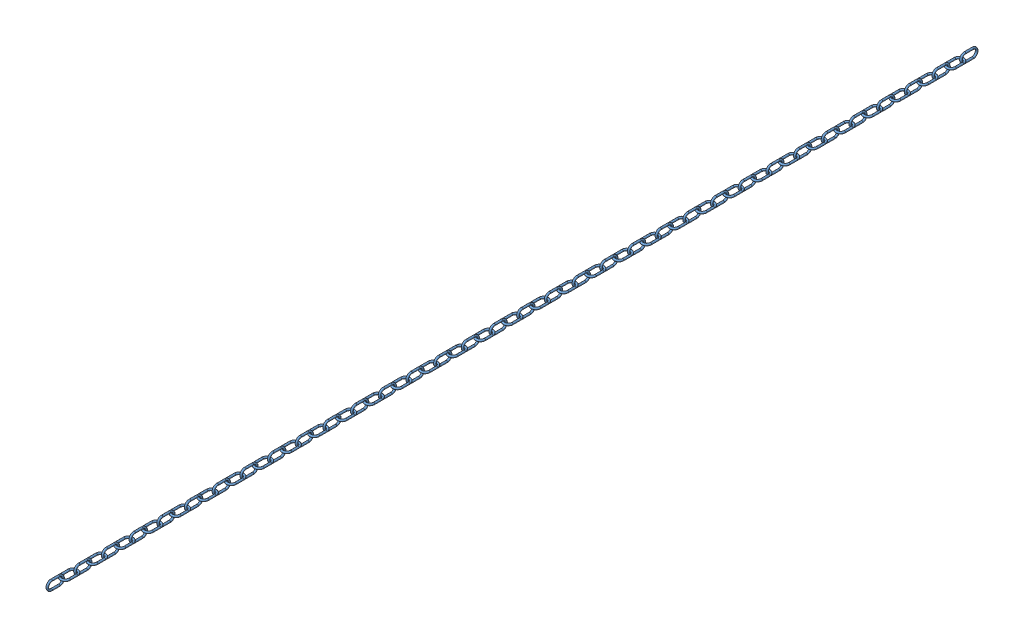
SolidWorks assembly GE-22026, configuration no u bolt. Lengths in mm.
Overall size (25.4 25.4 2349.5).
69 component instances, 2 part files, 9 mates.
Components (placement in the parent):
- GE-22355-01-1: GE-22355-01 [Default] at origin
- GE-22355-01-53: GE-22355-01 [Default] at (0 0 -34.925) x (0 1 0) z (0 0 1)
- GE-22355-01-19: GE-22355-01 [Default] at (0 0 -69.85)
- GE-22355-01-20: GE-22355-01 [Default] at (0 0 -139.7)
- GE-22355-01-21: GE-22355-01 [Default] at (0 0 -209.55)
- GE-22355-01-22: GE-22355-01 [Default] at (0 0 -279.4)
- GE-22355-01-23: GE-22355-01 [Default] at (0 0 -349.25)
- GE-22355-01-24: GE-22355-01 [Default] at (0 0 -419.1)
- GE-22355-01-25: GE-22355-01 [Default] at (0 0 -488.95)
- GE-22355-01-26: GE-22355-01 [Default] at (0 0 -558.8)
- GE-22355-01-27: GE-22355-01 [Default] at (0 0 -628.65)
- GE-22355-01-28: GE-22355-01 [Default] at (0 0 -698.5)
- GE-22355-01-29: GE-22355-01 [Default] at (0 0 -768.35)
- GE-22355-01-30: GE-22355-01 [Default] at (0 0 -838.2)
- GE-22355-01-31: GE-22355-01 [Default] at (0 0 -908.05)
- GE-22355-01-32: GE-22355-01 [Default] at (0 0 -977.9)
- GE-22355-01-33: GE-22355-01 [Default] at (0 0 -1047.75)
- GE-22355-01-54: GE-22355-01 [Default] at (0 0 -104.775) x (0 1 0) z (0 0 1)
- GE-22355-01-55: GE-22355-01 [Default] at (0 0 -174.625) x (0 1 0) z (0 0 1)
- GE-22355-01-56: GE-22355-01 [Default] at (0 0 -244.475) x (0 1 0) z (0 0 1)
- GE-22355-01-57: GE-22355-01 [Default] at (0 0 -314.325) x (0 1 0) z (0 0 1)
- GE-22355-01-58: GE-22355-01 [Default] at (0 0 -384.175) x (0 1 0) z (0 0 1)
- GE-22355-01-59: GE-22355-01 [Default] at (0 0 -454.025) x (0 1 0) z (0 0 1)
- GE-22355-01-60: GE-22355-01 [Default] at (0 0 -523.875) x (0 1 0) z (0 0 1)
- GE-22355-01-61: GE-22355-01 [Default] at (0 0 -593.725) x (0 1 0) z (0 0 1)
- GE-22355-01-62: GE-22355-01 [Default] at (0 0 -663.575) x (0 1 0) z (0 0 1)
- GE-22355-01-63: GE-22355-01 [Default] at (0 0 -733.425) x (0 1 0) z (0 0 1)
- GE-22355-01-64: GE-22355-01 [Default] at (0 0 -803.275) x (0 1 0) z (0 0 1)
- GE-22355-01-65: GE-22355-01 [Default] at (0 0 -873.125) x (0 1 0) z (0 0 1)
- GE-22355-01-66: GE-22355-01 [Default] at (0 0 -942.975) x (0 1 0) z (0 0 1)
- GE-22355-01-67: GE-22355-01 [Default] at (0 0 -1012.825) x (0 1 0) z (0 0 1)
- GE-22355-01-48: GE-22355-01 [Default] at (0 0 -1117.6)
- GE-22355-01-68: GE-22355-01 [Default] at (0 0 -1082.675) x (0 1 0) z (0 0 1)
- GE-22355-01-50: GE-22355-01 [Default] at (0 0 -1187.45)
- GE-22355-01-69: GE-22355-01 [Default] at (0 0 -1152.525) x (0 1 0) z (0 0 1)
- Ubolt_.25_.75_1.25-1: Ubolt_.25_.75_1.25 [3043T641] at (0 0 4.7625) x (-1 0 0) z (0 1 0) (suppressed, hidden)
- Ubolt_.25_.75_1.25-2: Ubolt_.25_.75_1.25 [3043T641] at (0 0 -1306.5125) x (-1 0 0) z (0 -1 0) (suppressed, hidden)
- GE-22355-01-52: GE-22355-01 [Default] at (0 0 -1257.3)
- GE-22355-01-70: GE-22355-01 [Default] at (0 0 -1222.375) x (0 1 0) z (0 0 1)
- GE-22355-01-71: GE-22355-01 [Default] at (0 0 -1327.15)
- GE-22355-01-72: GE-22355-01 [Default] at (0 0 -1397)
- GE-22355-01-73: GE-22355-01 [Default] at (0 0 -1466.85)
- GE-22355-01-74: GE-22355-01 [Default] at (0 0 -1536.7)
- GE-22355-01-75: GE-22355-01 [Default] at (0 0 -1606.55)
- GE-22355-01-76: GE-22355-01 [Default] at (0 0 -1676.4)
- GE-22355-01-77: GE-22355-01 [Default] at (0 0 -1746.25)
- GE-22355-01-78: GE-22355-01 [Default] at (0 0 -1816.1)
- GE-22355-01-79: GE-22355-01 [Default] at (0 0 -1885.95)
- GE-22355-01-80: GE-22355-01 [Default] at (0 0 -1955.8)
- GE-22355-01-81: GE-22355-01 [Default] at (0 0 -2025.65)
- GE-22355-01-82: GE-22355-01 [Default] at (0 0 -2095.5)
- GE-22355-01-83: GE-22355-01 [Default] at (0 0 -2165.35)
- GE-22355-01-84: GE-22355-01 [Default] at (0 0 -2235.2)
- GE-22355-01-85: GE-22355-01 [Default] at (0 0 -2305.05)
- GE-22355-01-88: GE-22355-01 [Default] at (0 0 -1292.225) x (0 1 0) z (0 0 1)
- GE-22355-01-89: GE-22355-01 [Default] at (0 0 -1362.075) x (0 1 0) z (0 0 1)
- GE-22355-01-90: GE-22355-01 [Default] at (0 0 -1431.925) x (0 1 0) z (0 0 1)
- GE-22355-01-91: GE-22355-01 [Default] at (0 0 -1501.775) x (0 1 0) z (0 0 1)
- GE-22355-01-92: GE-22355-01 [Default] at (0 0 -1571.625) x (0 1 0) z (0 0 1)
- GE-22355-01-93: GE-22355-01 [Default] at (0 0 -1641.475) x (0 1 0) z (0 0 1)
- GE-22355-01-94: GE-22355-01 [Default] at (0 0 -1711.325) x (0 1 0) z (0 0 1)
- GE-22355-01-95: GE-22355-01 [Default] at (0 0 -1781.175) x (0 1 0) z (0 0 1)
- GE-22355-01-96: GE-22355-01 [Default] at (0 0 -1851.025) x (0 1 0) z (0 0 1)
- GE-22355-01-97: GE-22355-01 [Default] at (0 0 -1920.875) x (0 1 0) z (0 0 1)
- GE-22355-01-98: GE-22355-01 [Default] at (0 0 -1990.725) x (0 1 0) z (0 0 1)
- GE-22355-01-99: GE-22355-01 [Default] at (0 0 -2060.575) x (0 1 0) z (0 0 1)
- GE-22355-01-100: GE-22355-01 [Default] at (0 0 -2130.425) x (0 1 0) z (0 0 1)
- GE-22355-01-101: GE-22355-01 [Default] at (0 0 -2200.275) x (0 1 0) z (0 0 1)
- GE-22355-01-102: GE-22355-01 [Default] at (0 0 -2270.125) x (0 1 0) z (0 0 1)
Mates (geometry in assembly coordinates):
- Coincident5: coincident anti-aligned: plane of low funnel chain-17 through (0 0 -1263.65) normal (0 0 -1)
- Coincident6: coincident anti-aligned: plane of low funnel chain-17 through (0 0 -1263.65) normal (0 -1 0)
- Coincident7: coincident aligned: plane of low funnel chain-17 through (0 0 -1263.65) normal (1 0 0)
- Coincident8: coincident anti-aligned: plane of low funnel chain-18 through (0 0 -34.925) normal (-1 0 0)
- Coincident9: coincident aligned: plane of low funnel chain-18 through (0 0 -34.925) normal (0 1 0)
- Distance1: distance = 34.925 mm: plane of assembly through (0 0 0) normal (0 0 1); plane of low funnel chain-18 through (0 0 -34.925) normal (0 0 1)
- Distance2: distance = 4.7625 mm aligned: plane of 3043T641_U-BOLT-1 through (0 0 -4.7625) normal (0 0 1)
- Coincident15: coincident anti-aligned: plane of 3043T641_U-BOLT-1 through (0 0 4.7625) normal (-1 0 0)
- Coincident17: coincident aligned: plane of 3043T641_U-BOLT-1 through (0 0 4.7625) normal (0 1 0)
